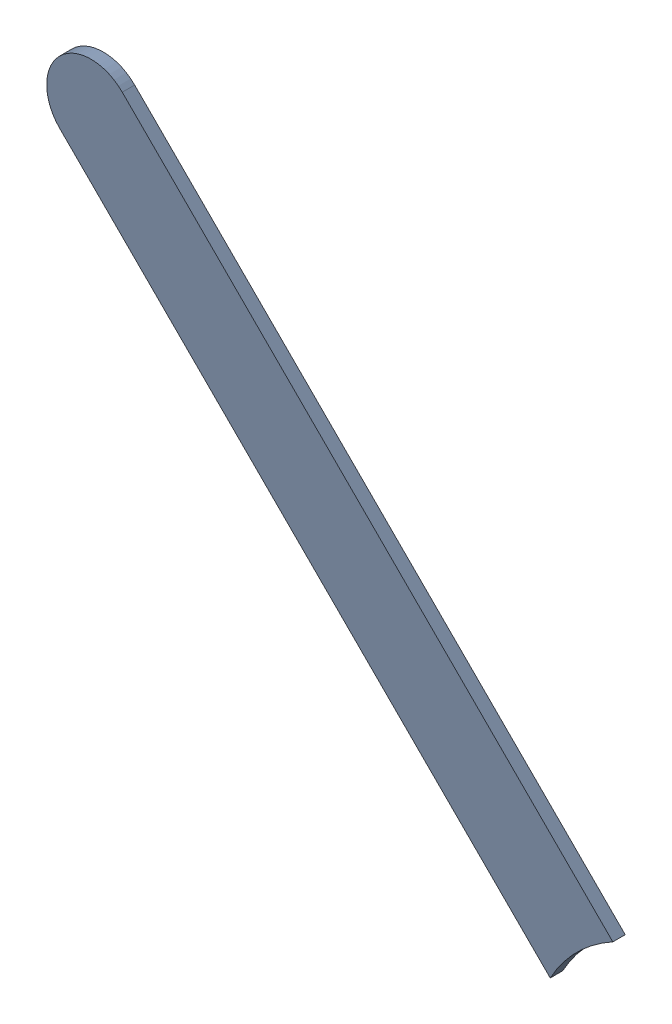
SolidWorks assembly Track (13.781mm,50.1mm)(15.494mm,48.387mm) on Top Layer, configuration Predeterminado. Lengths in mm.
Overall size (1.62 1.62 0.04).
2 component instances, 1 part files, 0 mates.
Components (placement in the parent):
- Track (13.781mm,50.1mm)(15.494mm,48.387mm) on Top Layer-1-1: Track (13.781mm,50.1mm)(15.494mm,48.387mm) on Top Layer-1 [Predeterminado] at (-68.317 -44.187 -0.0457) size (1.62 1.62 0.04)
  - Track (13.781mm,50.1mm)(15.494mm,48.387mm) on Top Layer-Part-1-1: Track (13.781mm,50.1mm)(15.494mm,48.387mm) on Top Layer-Part-1 [Predeterminado] at origin size (1.62 1.62 0.04)
